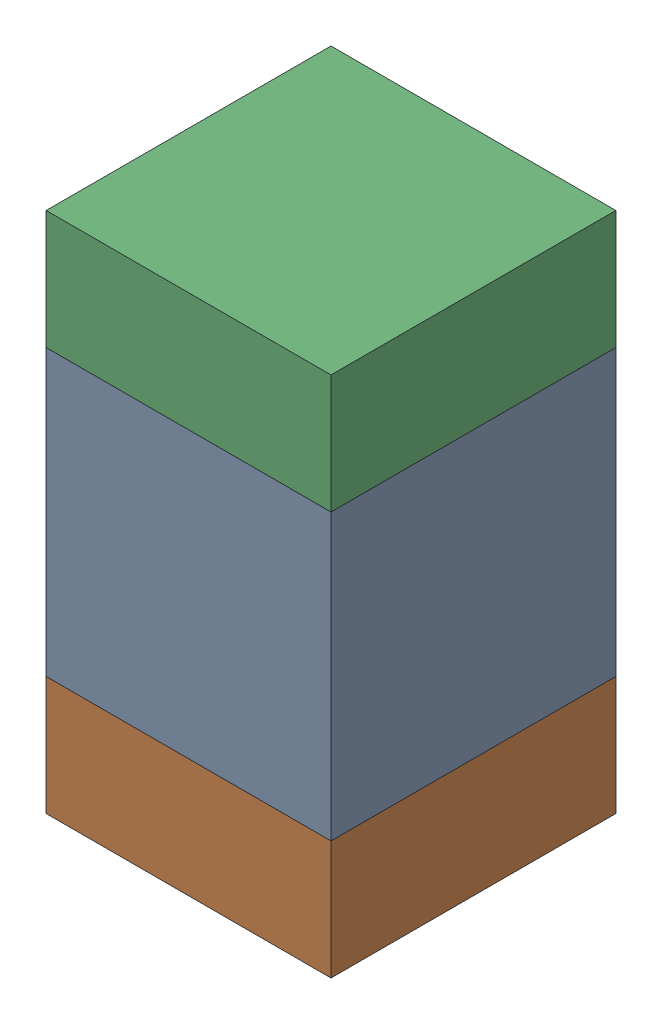
SolidWorks assembly C115_2PCB, configuration Default. Lengths in mm.
Overall size (0.6 1.1 0.6).
6 component instances, 2 part files, 0 mates.
Components (placement in the parent):
- 761606048-1: 761606048 [Default] at (114.7 88 0) size (0.6 0.6 0.6)
  - Extruded_9-1: Extruded_9 [Default] at origin size (0.6 0.6 0.6)
- 854785296-1: 854785296 [Default] at (114.7 87.575 0) size (0.6 0.25 0.6)
  - Extruded_10-1: Extruded_10 [Default] at origin size (0.6 0.25 0.6)
- 854785296-2: 854785296 [Default] at (114.7 88.425 0) size (0.6 0.25 0.6)
  - Extruded_10-1: Extruded_10 [Default] at origin size (0.6 0.25 0.6)
